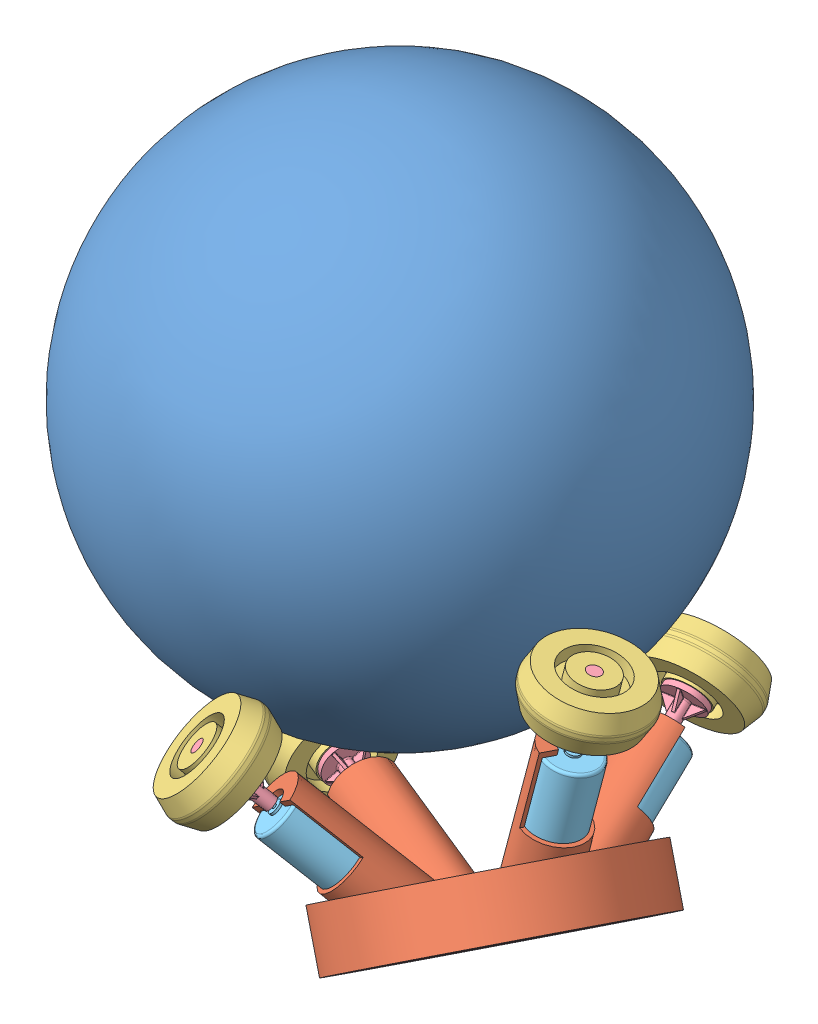
SolidWorks assembly Assem1, configuration Default. Lengths in mm.
Overall size (345.28 365.88 310.98).
19 component instances, 5 part files, 2 mates.
Components (placement in the parent):
- Basketball-1: Basketball [Default] at (57.1301 138.7732 195.5462) size (242.57 242.57 242.57)
- FourLegASM-1: FourLegASM [Default] at (175.3269 -75.4925 176.7509) x (0.799959 0.582822 0.142771) z (-0.274013 0.143135 0.951015) size (255.45 111.18 255.45)
  - FourLegBase-1: FourLegBase [Default] at (33.0096 39.469 80.9309) size (156.3 71.48 156.3)
  - MotorWheelASM-1: MotorWheelASM [Default] at (109.3139 70.0783 100.7456) x (0.5 -0.5 -0.707107) z (0.707107 0.707107 0) size (50.8 50.8 68.43)
    - Omni_Wheel-1: Omni_Wheel [Default] at (-0.5626 28.5849 47.8869) size (50.8 50.8 19.05)
    - MotorWheelCoupler-1: MotorWheelCoupler [Default] at (-0.5626 28.5849 35.8219) size (19.05 19.05 34.29)
    - DC_Motor-1: DC_Motor [Default] at (-0.5626 28.5849 -10.1267) size (24.38 24.38 40.49)
  - MotorWheelASM-2: MotorWheelASM [Default] at (13.1949 70.0783 157.2351) x (0.707107 -0.5 0.5) z (0 0.707107 0.707107) size (50.8 50.8 68.43)
    - Omni_Wheel-1: Omni_Wheel [Default] at (-0.5626 28.5849 47.8869) size (50.8 50.8 19.05)
    - MotorWheelCoupler-1: MotorWheelCoupler [Default] at (-0.5626 28.5849 35.8219) size (19.05 19.05 34.29)
    - DC_Motor-1: DC_Motor [Default] at (-0.5626 28.5849 -10.1267) size (24.38 24.38 40.49)
  - MotorWheelASM-3: MotorWheelASM [Default] at (-43.2946 70.0783 61.1161) x (-0.5 -0.5 0.707107) z (-0.707107 0.707107 0) size (50.8 50.8 68.43)
    - Omni_Wheel-1: Omni_Wheel [Default] at (-0.5626 28.5849 47.8869) size (50.8 50.8 19.05)
    - MotorWheelCoupler-1: MotorWheelCoupler [Default] at (-0.5626 28.5849 35.8219) size (19.05 19.05 34.29)
    - DC_Motor-1: DC_Motor [Default] at (-0.5626 28.5849 -10.1267) size (24.38 24.38 40.49)
  - MotorWheelASM-4: MotorWheelASM [Default] at (52.8244 70.0783 4.6266) x (-0.707107 -0.5 -0.5) z (0 0.707107 -0.707107) size (50.8 50.8 68.43)
    - Omni_Wheel-1: Omni_Wheel [Default] at (-0.5626 28.5849 47.8869) size (50.8 50.8 19.05)
    - MotorWheelCoupler-1: MotorWheelCoupler [Default] at (-0.5626 28.5849 35.8219) size (19.05 19.05 34.29)
    - DC_Motor-1: DC_Motor [Default] at (-0.5626 28.5849 -10.1267) size (24.38 24.38 40.49)
Mates (geometry in assembly coordinates):
- Concentric4: concentric: sphere of Basketball-1; cylinder of FourLegASM-1/FourLegBase-1 through (144.9277 7.2186 240.6429) axis (0.533837 -0.799894 0.274203) radius 63.5
- Distance2: distance = 43.18 mm anti-aligned: plane of FourLegASM-1/FourLegBase-1 through (144.9277 7.2186 240.6429) normal (-0.533837 0.799894 -0.274203); sphere of Basketball-1
